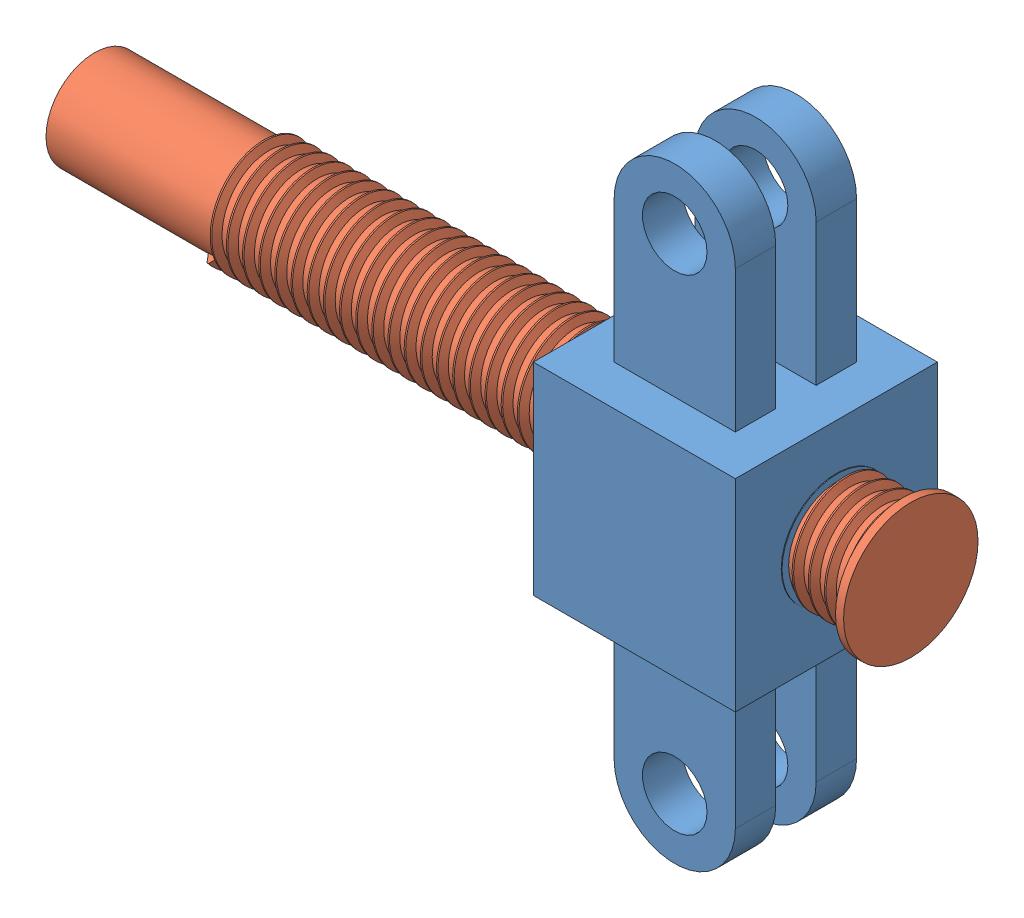
SolidWorks assembly SCREW TEST, configuration Default. Lengths in mm.
Overall size (101 75 25).
2 component instances, 2 part files, 1 mates.
Components (placement in the parent):
- link3-1: link3 [Default] at (-0.1622 41.2516 70.9921) size (26.24 75 25)
- linkscrew-1: linkscrew [Default] at (33.0467 53.7516 83.4921) x (0 -0.605098 0.796151) z (0 -0.796151 -0.605098) size (16.63 101 16.63)
Mates (geometry in assembly coordinates):
- Concentric1: concentric anti-aligned: circle of link3-1; circle of linkscrew-1
